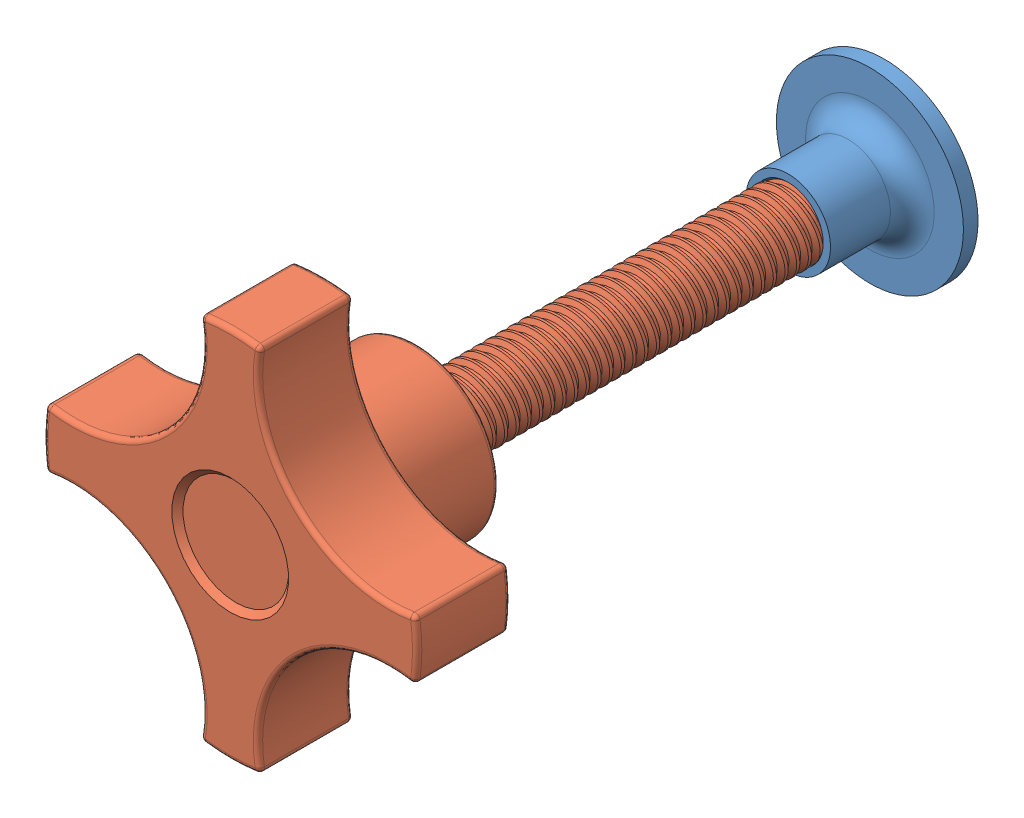
SolidWorks assembly Mold_Clamp, configuration Default. Lengths in mm.
Overall size (50.8 50.8 89.5).
2 component instances, 2 part files, 2 mates.
Components (placement in the parent):
- Base_Nut-1: Base_Nut [90596A031] at (6.4617 17.0716 12.0479) size (25.4 25.4 14.09)
- Four_Arm_Knob-1: Four_Arm_Knob [5993K59] at (6.4617 17.0716 43.7979) size (50.8 50.8 88.98)
Mates (geometry in assembly coordinates):
- Coincident3: coincident: plane of Base_Nut-1 through (6.4617 17.0716 12.0479) normal (0 0 -1); plane of Four_Arm_Knob-1 through (6.4617 21.8341 12.0479) normal (0 0 -1)
- Concentric1: concentric aligned: circle of Base_Nut-1; circle of Four_Arm_Knob-1
